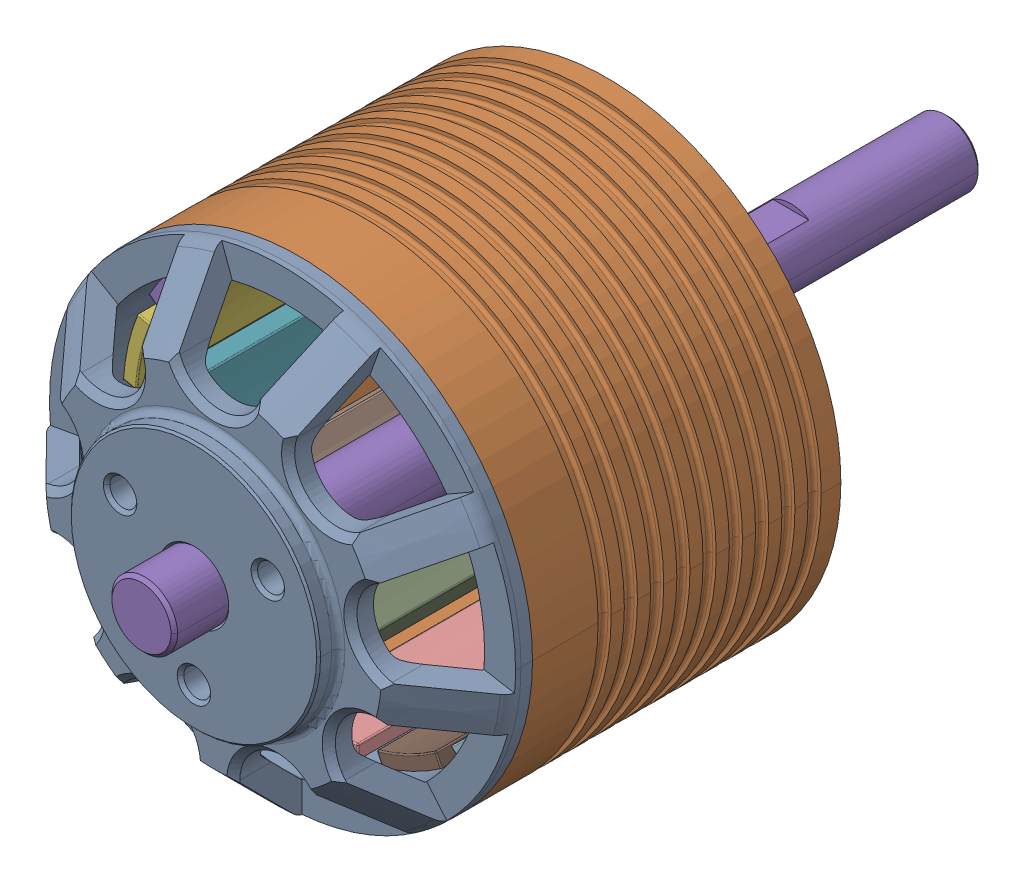
SolidWorks assembly 2820-Rotor-Assem.STEP, configuration Default. Lengths in mm.
Overall size (35.6 35.6 61.5).
17 component instances, 4 part files, 0 mates.
Components (placement in the parent):
- 28mm-Endbell-9.STEP-1: 28mm-Endbell-9.STEP [Default] at (15.292 17.5059 -27.2126) size (35.6 35.6 14.5)
- 2820-Fluxring.STEP-1: 2820-Fluxring.STEP [Default] at (15.292 17.5059 -44.2126) size (35.6 35.6 23.5)
- 2820-Magnet.STEP-1: 2820-Magnet.STEP [Default] at (15.292 17.5059 -42.7126) size (5 2.2 20)
- 2820-Magnet.STEP-2: 2820-Magnet.STEP [Default] at (15.292 17.5059 -42.7126) x (0.900969 0.433884 0) z (0 0 1) size (5 2.2 20)
- 2820-Magnet.STEP-3: 2820-Magnet.STEP [Default] at (15.292 17.5059 -42.7126) x (0.62349 0.781831 0) z (0 0 1) size (5 2.2 20)
- 2820-Magnet.STEP-4: 2820-Magnet.STEP [Default] at (15.292 17.5059 -42.7126) x (0.222521 0.974928 0) z (0 0 1) size (5 2.2 20)
- 2820-Magnet.STEP-5: 2820-Magnet.STEP [Default] at (15.292 17.5059 -42.7126) x (-0.222521 0.974928 0) z (0 0 1) size (5 2.2 20)
- 2820-Magnet.STEP-6: 2820-Magnet.STEP [Default] at (15.292 17.5059 -42.7126) x (-0.62349 0.781831 0) z (0 0 1) size (5 2.2 20)
- 2820-Magnet.STEP-7: 2820-Magnet.STEP [Default] at (15.292 17.5059 -42.7126) x (-0.900969 0.433884 0) z (0 0 1) size (5 2.2 20)
- 2820-Magnet.STEP-8: 2820-Magnet.STEP [Default] at (15.292 17.5059 -42.7126) x (-1 0 0) z (0 0 1) size (5 2.2 20)
- 2820-Magnet.STEP-9: 2820-Magnet.STEP [Default] at (15.292 17.5059 -42.7126) x (-0.900969 -0.433884 0) z (0 0 1) size (5 2.2 20)
- 2820-Magnet.STEP-10: 2820-Magnet.STEP [Default] at (15.292 17.5059 -42.7126) x (-0.62349 -0.781831 0) z (0 0 1) size (5 2.2 20)
- 2820-Magnet.STEP-11: 2820-Magnet.STEP [Default] at (15.292 17.5059 -42.7126) x (-0.222521 -0.974928 0) z (0 0 1) size (5 2.2 20)
- 2820-Magnet.STEP-12: 2820-Magnet.STEP [Default] at (15.292 17.5059 -42.7126) x (0.222521 -0.974928 0) z (0 0 1) size (5 2.2 20)
- 2820-Magnet.STEP-13: 2820-Magnet.STEP [Default] at (15.292 17.5059 -42.7126) x (0.62349 -0.781831 0) z (0 0 1) size (5 2.2 20)
- 2820-Magnet.STEP-14: 2820-Magnet.STEP [Default] at (15.292 17.5059 -42.7126) x (0.900969 -0.433884 0) z (0 0 1) size (5 2.2 20)
- 2820-Shaft.STEP-1: 2820-Shaft.STEP [Default] at (15.292 17.5059 -70.2126) size (5 5 61.5)
